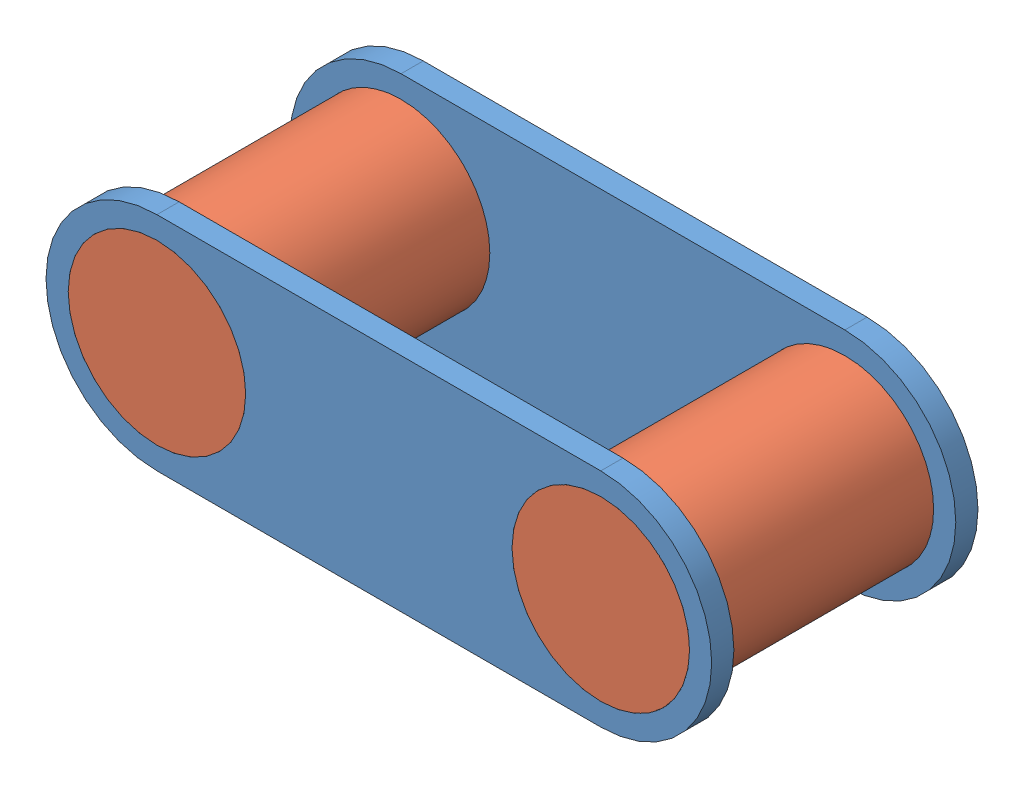
SolidWorks assembly SmallLinkageChain, configuration Default. Lengths in mm.
Overall size (38.1 12.7 15.24).
4 component instances, 2 part files, 7 mates.
Components (placement in the parent):
- LinkagePart-1: LinkagePart [Default] at (73.4379 54.8795 -38.979) size (38.1 12.7 1.27)
- SmallLinkCylinder-1: SmallLinkCylinder [Default] at (24.7536 -17.0726 -38.979) size (10.16 10.16 15.24)
- SmallLinkCylinder-2: SmallLinkCylinder [Default] at (-0.6464 -17.0726 -38.979) size (10.16 10.16 15.24)
- LinkagePart-2: LinkagePart [Default] at (73.4379 54.8795 -25.009) size (38.1 12.7 1.27)
Mates (geometry in assembly coordinates):
- Concentric1: concentric aligned: cylinder of LinkagePart-1 through (-10.1733 -3.0625 -37.709) axis (0 0 -1) radius 5.08; cylinder of SmallLinkCylinder-2 through (-10.1733 -3.0625 -23.739) axis (0 0 -1) radius 5.08
- Coincident1: coincident aligned: plane of LinkagePart-1 through (-10.1733 -3.0625 -38.979) normal (0 0 -1); plane of SmallLinkCylinder-2 through (-10.1733 -3.0625 -38.979) normal (0 0 -1)
- Concentric2: concentric aligned: cylinder of LinkagePart-1 through (15.2267 -3.0625 -37.709) axis (0 0 -1) radius 5.08; cylinder of SmallLinkCylinder-1 through (15.2267 -3.0625 -23.739) axis (0 0 -1) radius 5.08
- Coincident2: coincident aligned: plane of LinkagePart-1 through (-10.1733 -3.0625 -38.979) normal (0 0 -1); plane of SmallLinkCylinder-1 through (15.2267 -3.0625 -38.979) normal (0 0 -1)
- Concentric3: concentric aligned: cylinder of SmallLinkCylinder-1 through (15.2267 -3.0625 -23.739) axis (0 0 -1) radius 5.08; cylinder of LinkagePart-2 through (15.2267 -3.0625 -18.0127) axis (0 0 -1) radius 5.08
- Concentric5: concentric aligned: cylinder of SmallLinkCylinder-2 through (-10.1733 -3.0625 -23.739) axis (0 0 -1) radius 5.08; cylinder of LinkagePart-2 through (-10.1733 -3.0625 -18.0127) axis (0 0 -1) radius 5.08
- Symmetric1: symmetric anti-aligned: plane of SmallLinkCylinder-1 through (15.2267 -3.0625 -23.739) normal (0 0 1); plane of SmallLinkCylinder-2 through (-10.1733 -3.0625 -23.739) normal (0 0 1); plane of LinkagePart-2 through (-10.1733 -3.0625 -23.739) normal (0 0 1)
